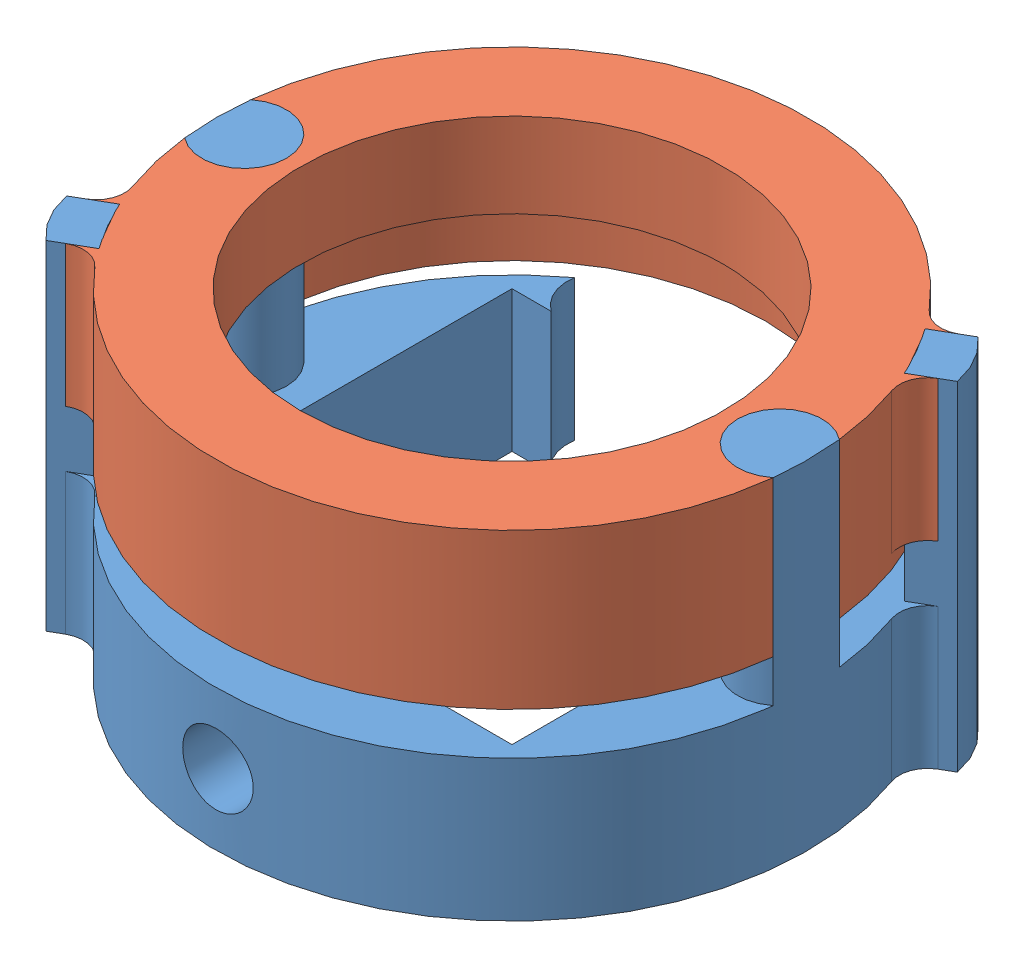
SolidWorks assembly Assem1, configuration Default. Lengths in mm.
Overall size (21.49 12 21).
2 component instances, 2 part files, 3 mates.
Components (placement in the parent):
- lamp holder-1: lamp holder [Default] at (4.6954 4.1485 17.9464) size (21.49 12 18.95)
- lamp holder front-1: lamp holder front [Default] at (4.6954 11.1485 17.9464) size (20.87 5.5 21)
Mates (geometry in assembly coordinates):
- Concentric1: concentric: cylinder of lamp holder-1 through (14.1954 16.1485 17.9464) axis (0 -1 0) radius 1.5; cylinder of lamp holder front-1 through (14.1954 10.6485 17.9464) axis (0 1 0) radius 1.5
- Concentric2: concentric: cylinder of lamp holder-1 through (-4.8046 16.1485 17.9464) axis (0 -1 0) radius 1.5; cylinder of lamp holder front-1 through (-4.8046 10.6485 17.9464) axis (0 1 0) radius 1.5
- Coincident1: coincident: plane of lamp holder-1 through (4.6954 16.1485 17.9464) normal (0 1 0); plane of lamp holder front-1 through (4.6954 16.1485 17.9464) normal (0 1 0)
